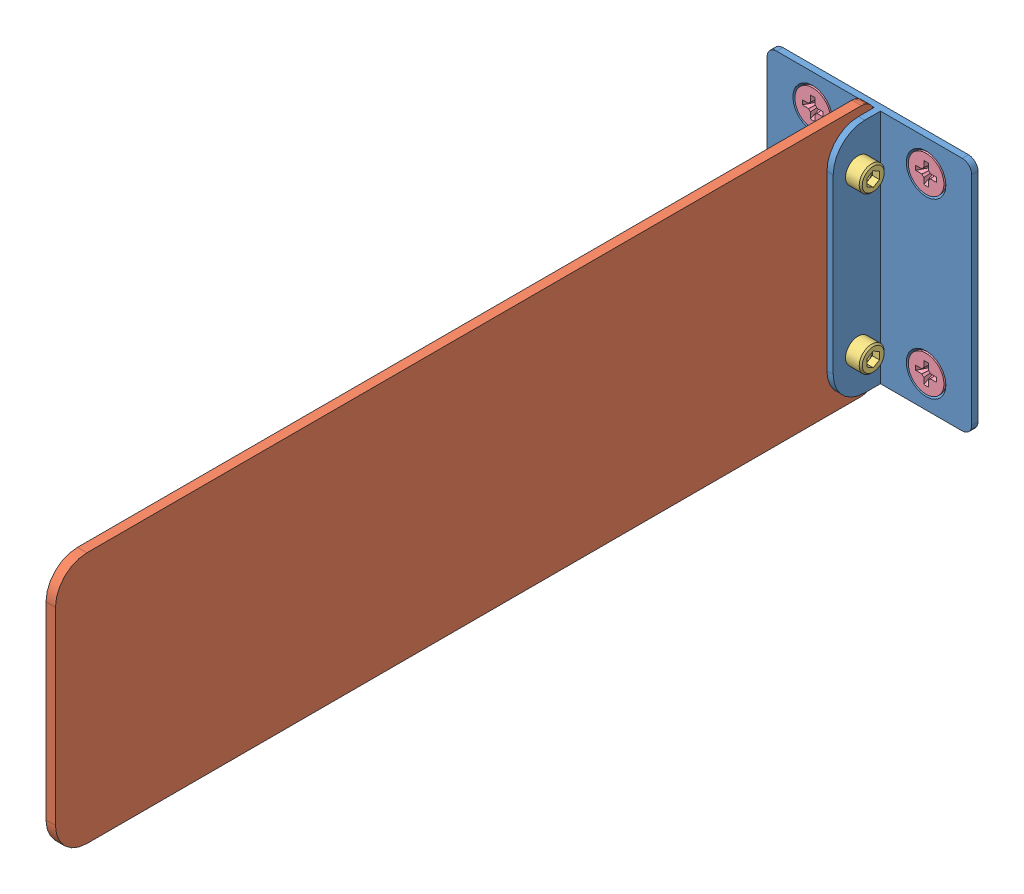
SolidWorks assembly signaletiquemontee, configuration Défaut. Lengths in mm.
Overall size (65 80 268).
8 component instances, 4 part files, 10 mates.
Components (placement in the parent):
- support panneau salle 1-1: support panneau salle 1 [Défaut] at (-30.5033 -37.013 66.5) size (65 75 31.9)
- signeattente-1: signeattente [Défaut] at (3.4735 -39.5191 68.5) x (0 0 1) z (-1 0 0) size (260 80 3)
- socket head cap screw_ai-1: socket head cap screw_ai [HX-SHCS 0.19-32x0.3125x0.3125-N] at (10.346 25.2992 75.6337) x (-1 0 0) z (0 0 -1) size (12.76 7.94 7.94)
- socket head cap screw_ai-2: socket head cap screw_ai [HX-SHCS 0.19-32x0.3125x0.3125-N] at (10.346 -24.3252 75.6337) x (-1 0 0) z (0 0 -1) size (12.76 7.94 7.94)
- countersunk flat head cross recess screw_iso-1: countersunk flat head cross recess screw_iso [ISO 7046-1 - M6 x 8 - Z - 8N] at (-16.0149 27.987 68.5) x (0 0 -1) z (1 0 0) size (8 11.3 11.3)
- countersunk flat head cross recess screw_iso-2: countersunk flat head cross recess screw_iso [ISO 7046-1 - M6 x 8 - Z - 8N] at (-16.0149 -27.013 68.5) x (0 0 -1) z (1 0 0) size (8 11.3 11.3)
- countersunk flat head cross recess screw_iso-3: countersunk flat head cross recess screw_iso [ISO 7046-1 - M6 x 8 - Z - 8N] at (20.0083 -27.013 68.5) x (0 0 -1) z (1 0 0) size (8 11.3 11.3)
- countersunk flat head cross recess screw_iso-4: countersunk flat head cross recess screw_iso [ISO 7046-1 - M6 x 8 - Z - 8N] at (20.0083 27.987 68.5) x (0 0 -1) z (1 0 0) size (8 11.3 11.3)
Mates (geometry in assembly coordinates):
- Coïncidente1: coincident: plane of support panneau salle 1-1 through (0.4735 37.987 83.5) normal (1 0 0); plane of signeattente-1 through (0.4735 -39.5191 68.5) normal (-1 0 0)
- Coïncidente2: coincident: plane of support panneau salle 1-1 through (-30.5033 -37.013 68.5) normal (0 0 1); plane of signeattente-1 through (0.4735 -39.5191 68.5) normal (0 0 -1)
- Coaxiale11: concentric: cylinder of support panneau salle 1-1 through (-9.48 25.2992 75.6337) axis (1 0 0) radius 3; cylinder of socket head cap screw_ai-1 through (42.096 25.2992 75.6337) axis (1 0 0) radius 2.413
- Coïncidente31: coincident: plane of support panneau salle 1-1 through (5.52 37.987 83.5) normal (1 0 0); plane of socket head cap screw_ai-1 through (5.52 29.268 75.6337) normal (-1 0 0)
- Coaxiale21: concentric: cylinder of support panneau salle 1-1 through (-9.48 -24.3252 75.6337) axis (1 0 0) radius 3; cylinder of socket head cap screw_ai-2 through (42.096 -24.3252 75.6337) axis (1 0 0) radius 2.413
- Coïncidente41: coincident: plane of support panneau salle 1-1 through (5.52 37.987 83.5) normal (1 0 0); plane of socket head cap screw_ai-2 through (5.52 -20.3565 75.6337) normal (-1 0 0)
- Coïncidente5: coincident: cone of support panneau salle 1-1 through (-16.0149 27.987 68.5) axis (0 0 -1); cone of countersunk flat head cross recess screw_iso-1 through (-16.0149 27.987 67.85) axis (0 0 -1)
- Coïncidente6: coincident: cone of support panneau salle 1-1 through (-16.0149 -27.013 68.5) axis (0 0 -1); cone of countersunk flat head cross recess screw_iso-2 through (-16.0149 -27.013 67.85) axis (0 0 -1)
- Coïncidente7: coincident: cone of support panneau salle 1-1 through (20.0083 -27.013 68.5) axis (0 0 -1); cone of countersunk flat head cross recess screw_iso-3 through (20.0083 -27.013 67.85) axis (0 0 -1)
- Coïncidente8: coincident: cone of support panneau salle 1-1 through (20.0083 27.987 68.5) axis (0 0 -1); cone of countersunk flat head cross recess screw_iso-4 through (20.0083 27.987 67.85) axis (0 0 -1)
